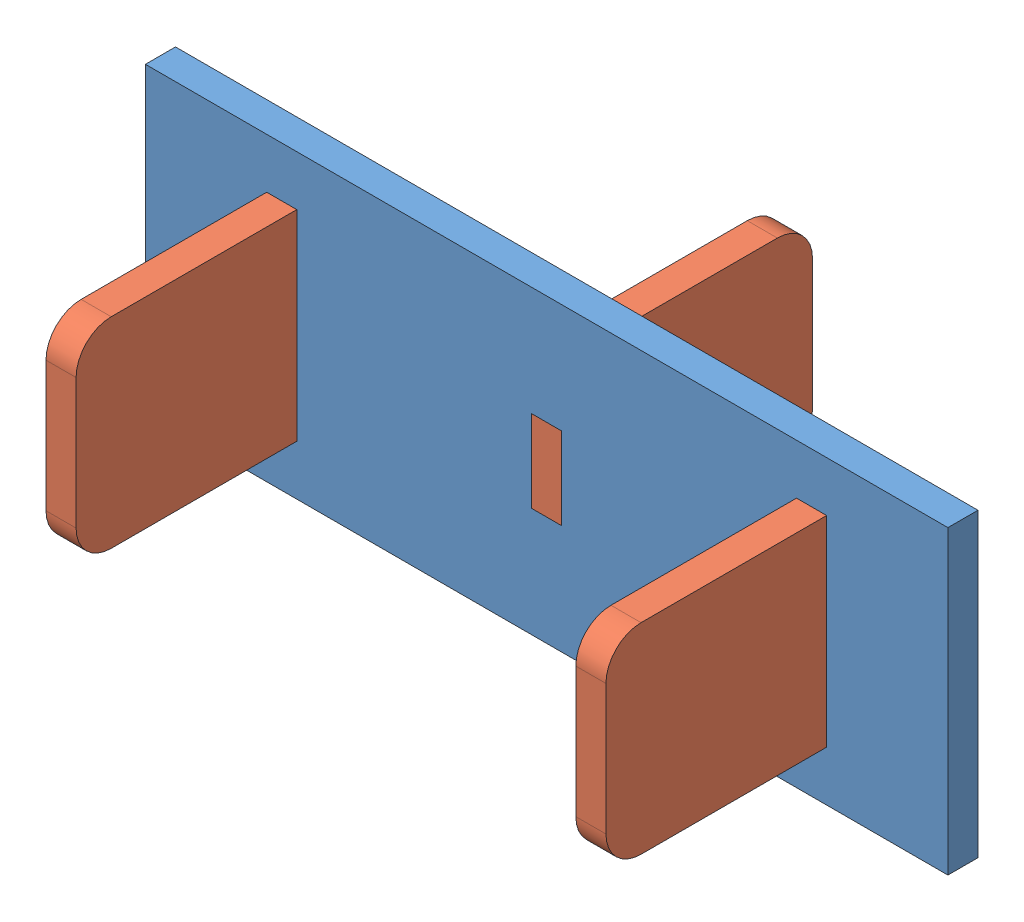
SolidWorks assembly Assem1, configuration Default. Lengths in mm.
Overall size (80 30 47).
4 component instances, 2 part files, 6 mates.
Components (placement in the parent):
- M-DPE-005-Mock Rack Piece A-1: M-DPE-005-Mock Rack Piece A [Default] at origin size (80 30 3)
- M-DPE-005-Mock Rack Piece B-1: M-DPE-005-Mock Rack Piece B [Default] at (-27.91 0 14) size (3 20 25)
- M-DPE-005-Mock Rack Piece B-2: M-DPE-005-Mock Rack Piece B [Default] at (24.91 0 14) size (3 20 25)
- M-DPE-005-Mock Rack Piece B-3: M-DPE-005-Mock Rack Piece B [Default] at (1.5 0 -11) x (-1 0 0) z (0 0 -1) size (3 20 25)
Mates (geometry in assembly coordinates):
- Width1: width anti-aligned: plane of M-DPE-005-Mock Rack Piece B-1 through (-24.91 4.09 3) normal (0 1 0); plane of M-DPE-005-Mock Rack Piece A-1 through (-24.91 -4.09 0) normal (0 -1 0); plane of M-DPE-005-Mock Rack Piece B-1 through (-27.82 3.9 3) normal (0 -1 0); plane of M-DPE-005-Mock Rack Piece A-1 through (-27.82 -3.9 3) normal (0 1 0)
- Width2: width anti-aligned: plane of M-DPE-005-Mock Rack Piece B-1 through (-24.91 0 14) normal (1 0 0); plane of M-DPE-005-Mock Rack Piece A-1 through (-27.91 0 14) normal (-1 0 0); plane of M-DPE-005-Mock Rack Piece B-1 through (-25 3.9 3) normal (-1 0 0); plane of M-DPE-005-Mock Rack Piece A-1 through (-27.82 3.9 3) normal (1 0 0)
- Coincident1: coincident anti-aligned: plane of M-DPE-005-Mock Rack Piece A-1 through (0 0 3) normal (0 0 1); plane of M-DPE-005-Mock Rack Piece B-1 through (-24.91 10 3) normal (0 0 -1)
- Width3: width: plane of M-DPE-005-Mock Rack Piece B-3 through (-1.5 4.09 0) normal (0 1 0); plane of M-DPE-005-Mock Rack Piece A-1 through (-1.5 -4.09 3) normal (0 -1 0); plane of M-DPE-005-Mock Rack Piece B-3 through (-1.41 -3.9 3) normal (0 1 0); plane of M-DPE-005-Mock Rack Piece A-1 through (-1.41 3.9 3) normal (0 -1 0)
- Width4: width: plane of M-DPE-005-Mock Rack Piece B-3 through (1.5 0 -11) normal (1 0 0); plane of M-DPE-005-Mock Rack Piece A-1 through (-1.5 0 -11) normal (-1 0 0); plane of M-DPE-005-Mock Rack Piece B-3 through (1.41 -3.9 3) normal (-1 0 0); plane of M-DPE-005-Mock Rack Piece A-1 through (-1.41 -3.9 3) normal (1 0 0)
- Coincident2: coincident aligned: plane of M-DPE-005-Mock Rack Piece A-1 through (0 0 3) normal (0 0 1); plane of M-DPE-005-Mock Rack Piece B-3 through (-1.5 4.09 3) normal (0 0 1)
